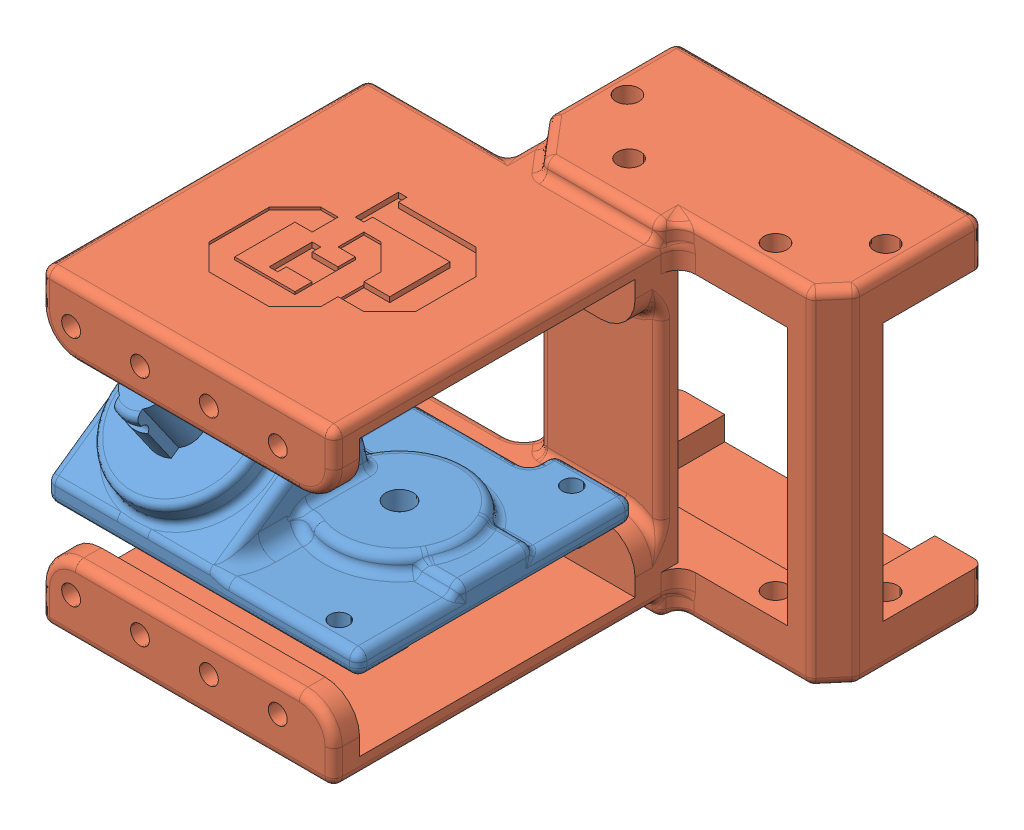
SolidWorks assembly Shapeways Print Assembly - Camera Bracket and Old Grip, configuration Default. Lengths in mm.
Overall size (54 40 57.6).
2 component instances, 2 part files, 3 mates.
Components (placement in the parent):
- Camera Bracket - Mount on AX-12-1: Camera Bracket - Mount on AX-12 [Default] at origin size (36.2 17.83 32.99)
- Custom Frame - RX-28 to AX-12 for Old Gripper-1: Custom Frame - RX-28 to AX-12 for Old Gripper [Default] at (26.2 20.78 -36.9596) x (0 0 1) z (-1 0 0) size (57.6 40 51.8)
Mates (geometry in assembly coordinates):
- Distance1: distance = 7.62 mm anti-aligned: plane of Camera Bracket - Mount on AX-12-1 through (-10 -2.6 9) normal (0 -1 0); plane of Custom Frame - RX-28 to AX-12 for Old Gripper-1 through (26.2 -10.22 -26.1596) normal (0 1 0)
- Coincident2: coincident aligned: plane of Camera Bracket - Mount on AX-12-1 through (26.2 -2.6 -23) normal (1 0 0); plane of Custom Frame - RX-28 to AX-12 for Old Gripper-1 through (26.2 5.78 -26.1596) normal (1 0 0)
- Distance2: distance = 2.8404 mm aligned: plane of Camera Bracket - Mount on AX-12-1 through (26.2 -2.6 9) normal (0 0 1); plane of Custom Frame - RX-28 to AX-12 for Old Gripper-1 through (26.2 -4.22 11.8404) normal (0 0 1)
